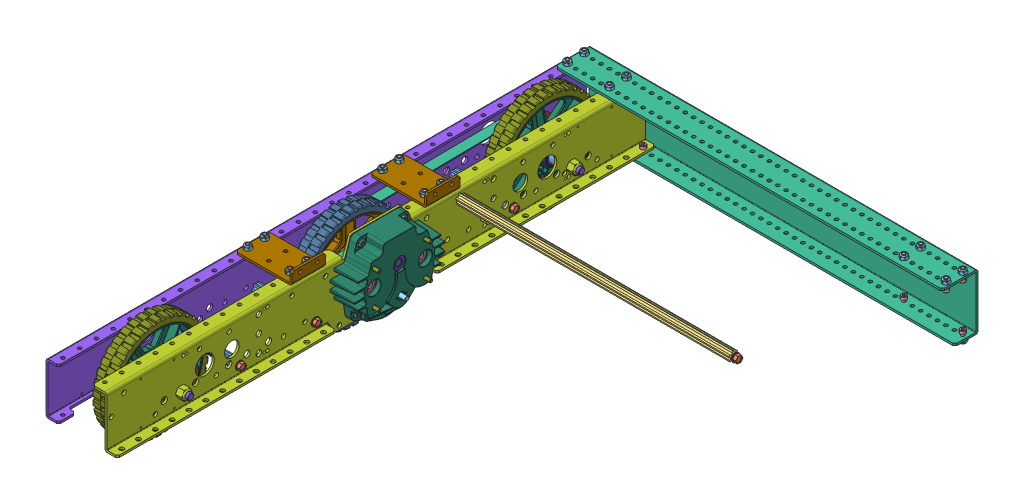
SolidWorks assembly AM14U3Long_Half, configuration Default. Lengths in mm.
Overall size (596.72 219.18 816.74).
154 component instances, 37 part files, 6 mates.
Components (placement in the parent):
- AM14U3Long_Frame_Half-1: AM14U3Long_Frame_Half [Default] at (0 136.144 -762.762) size (596.14 116.33 816.74)
  - 500Churro_3.375-1: 500Churro_3.375 [Default] at (-501.65 -66.929 448.437) x (0 0 1) z (-1 0 0) size (14.66 12.7 85.72)
  - 500Churro_3.375-2: 500Churro_3.375 [Default] at (-501.65 -66.929 562.737) x (0 0 1) z (-1 0 0) size (14.66 12.7 85.72)
  - 500Churro_3.375-3: 500Churro_3.375 [Default] at (-501.65 -66.929 264.287) x (0 0 1) z (-1 0 0) size (14.66 12.7 85.72)
  - 500Churro_3.375-4: 500Churro_3.375 [Default] at (-501.65 -66.929 149.987) x (0 0 1) z (-1 0 0) size (14.66 12.7 85.72)
  - ThreadRollingScrew_0.25-20x0.75_FHTS 0.25-20-G-0.75-C-1: ThreadRollingScrew_0.25-20x0.75_FHTS 0.25-20-G-0.75-C [Default] at (-498.475 -66.929 562.737) x (-1 0 0) z (0 0.924225 0.381849) size (24.64 12.19 12.19)
  - ThreadRollingScrew_0.25-20x0.75_FHTS 0.25-20-G-0.75-C-2: ThreadRollingScrew_0.25-20x0.75_FHTS 0.25-20-G-0.75-C [Default] at (-498.475 -66.929 448.437) x (-1 0 0) z (0 0.924225 0.381849) size (24.64 12.19 12.19)
  - ThreadRollingScrew_0.25-20x0.75_FHTS 0.25-20-G-0.75-C-3: ThreadRollingScrew_0.25-20x0.75_FHTS 0.25-20-G-0.75-C [Default] at (-498.475 -66.929 264.287) x (-1 0 0) z (0 0.924225 0.381849) size (24.64 12.19 12.19)
  - ThreadRollingScrew_0.25-20x0.75_FHTS 0.25-20-G-0.75-C-4: ThreadRollingScrew_0.25-20x0.75_FHTS 0.25-20-G-0.75-C [Default] at (-498.475 -66.929 149.987) x (-1 0 0) z (0 0.924225 0.381849) size (24.64 12.19 12.19)
  - ThreadRollingScrew_0.25-20x0.75_FHTS 0.25-20-G-0.75-C-5: ThreadRollingScrew_0.25-20x0.75_FHTS 0.25-20-G-0.75-C [Default] at (-590.55 -66.929 562.737) size (24.64 12.19 12.19)
  - ThreadRollingScrew_0.25-20x0.75_FHTS 0.25-20-G-0.75-C-6: ThreadRollingScrew_0.25-20x0.75_FHTS 0.25-20-G-0.75-C [Default] at (-590.55 -66.929 448.437) size (24.64 12.19 12.19)
  - ThreadRollingScrew_0.25-20x0.75_FHTS 0.25-20-G-0.75-C-7: ThreadRollingScrew_0.25-20x0.75_FHTS 0.25-20-G-0.75-C [Default] at (-590.55 -66.929 149.987) size (24.64 12.19 12.19)
  - ThreadRollingScrew_0.25-20x0.75_FHTS 0.25-20-G-0.75-C-8: ThreadRollingScrew_0.25-20x0.75_FHTS 0.25-20-G-0.75-C [Default] at (-590.55 -66.929 264.287) size (24.64 12.19 12.19)
  - ThreadRollingScrew_0.25-20x0.75_FHTS 0.25-20-G-0.75-C-9: ThreadRollingScrew_0.25-20x0.75_FHTS 0.25-20-G-0.75-C [Default] at (-501.65 -15.494 229.362) size (24.64 12.19 12.19)
  - ThreadRollingScrew_0.25-20x0.75_FHTS 0.25-20-G-0.75-C-10: ThreadRollingScrew_0.25-20x0.75_FHTS 0.25-20-G-0.75-C [Default] at (-82.55 -15.494 229.362) x (-1 0 0) z (0 -0.924225 -0.381849) size (24.64 12.19 12.19)
  - 500Churro_cut_16.25-1: 500Churro_cut_16.25 [Default] at (-85.725 -15.494 229.362) x (0 0.99241 0.122972) z (-1 0 0) size (14.66 12.7 412.75)
  - Screw_SHCS_10-32x0.5_HX-SHCS 0.19-32x1.375x1-C-1: Screw_SHCS_10-32x0.5_HX-SHCS 0.19-32x1.375x1-C [Default] at (-577.85 -11.43 -11.938) x (0 1 0) z (0 0 1) size (17.53 7.94 7.94)
  - Screw_SHCS_10-32x0.5_HX-SHCS 0.19-32x1.375x1-C-2: Screw_SHCS_10-32x0.5_HX-SHCS 0.19-32x1.375x1-C [Default] at (-577.85 -11.43 -37.338) x (0 1 0) z (0 0 1) size (17.53 7.94 7.94)
  - Screw_SHCS_10-32x0.5_HX-SHCS 0.19-32x1.375x1-C-3: Screw_SHCS_10-32x0.5_HX-SHCS 0.19-32x1.375x1-C [Default] at (-514.35 -11.43 -37.338) x (0 1 0) z (0 0 1) size (17.53 7.94 7.94)
  - Screw_SHCS_10-32x0.5_HX-SHCS 0.19-32x1.375x1-C-4: Screw_SHCS_10-32x0.5_HX-SHCS 0.19-32x1.375x1-C [Default] at (-514.35 -11.43 -11.938) x (0 1 0) z (0 0 1) size (17.53 7.94 7.94)
  - Screw_SHCS_10-32x0.5_HX-SHCS 0.19-32x1.375x1-C-5: Screw_SHCS_10-32x0.5_HX-SHCS 0.19-32x1.375x1-C [Default] at (-488.95 -73.152 -37.338) x (0 -1 0) z (0 0 1) size (17.53 7.94 7.94)
  - Screw_SHCS_10-32x0.5_HX-SHCS 0.19-32x1.375x1-C-6: Screw_SHCS_10-32x0.5_HX-SHCS 0.19-32x1.375x1-C [Default] at (-577.85 -73.152 -37.338) x (0 -1 0) z (0 0 1) size (17.53 7.94 7.94)
  - Screw_SHCS_10-32x0.5_HX-SHCS 0.19-32x1.375x1-C-7: Screw_SHCS_10-32x0.5_HX-SHCS 0.19-32x1.375x1-C [Default] at (-6.35 -11.176 -11.938) x (0 1 0) z (-0.991845 0 0.127447) size (17.53 7.94 7.94)
  - Screw_SHCS_10-32x0.5_HX-SHCS 0.19-32x1.375x1-C-8: Screw_SHCS_10-32x0.5_HX-SHCS 0.19-32x1.375x1-C [Default] at (-6.35 -11.176 -37.338) x (0 1 0) z (0.595464 0 0.803382) size (17.53 7.94 7.94)
  - Screw_SHCS_10-32x0.5_HX-SHCS 0.19-32x1.375x1-C-9: Screw_SHCS_10-32x0.5_HX-SHCS 0.19-32x1.375x1-C [Default] at (-69.85 -11.176 -11.938) x (0 1 0) z (0.578861 0 0.815426) size (17.53 7.94 7.94)
  - Screw_SHCS_10-32x0.5_HX-SHCS 0.19-32x1.375x1-C-10: Screw_SHCS_10-32x0.5_HX-SHCS 0.19-32x1.375x1-C [Default] at (-69.85 -11.176 -37.338) x (0 1 0) z (0.958905 0 0.283727) size (17.53 7.94 7.94)
  - Screw_SHCS_10-32x0.5_HX-SHCS 0.19-32x1.375x1-C-11: Screw_SHCS_10-32x0.5_HX-SHCS 0.19-32x1.375x1-C [Default] at (-6.35 -73.406 -37.338) x (0 -1 0) z (-0.989362 0 -0.145473) size (17.53 7.94 7.94)
  - Screw_SHCS_10-32x0.5_HX-SHCS 0.19-32x1.375x1-C-12: Screw_SHCS_10-32x0.5_HX-SHCS 0.19-32x1.375x1-C [Default] at (-95.25 -73.406 -37.338) x (0 -1 0) z (-0.875347 0 0.483496) size (17.53 7.94 7.94)
  - NylockNut_10-32-1: NylockNut_10-32 [Default] at (-69.85 0 -11.938) x (1 0 0) z (0 1 0) size (9.53 11 5.96)
  - NylockNut_10-32-2: NylockNut_10-32 [Default] at (-69.85 0 -37.338) x (1 0 0) z (0 1 0) size (9.53 11 5.96)
  - NylockNut_10-32-3: NylockNut_10-32 [Default] at (-6.35 0 -37.338) x (1 0 0) z (0 1 0) size (9.53 11 5.96)
  - NylockNut_10-32-4: NylockNut_10-32 [Default] at (-6.35 0 -11.938) x (1 0 0) z (0 1 0) size (9.53 11 5.96)
  - NylockNut_10-32-5: NylockNut_10-32 [Default] at (-6.35 -84.582 -37.338) x (1 0 0) z (0 -1 0) size (9.53 11 5.96)
  - NylockNut_10-32-6: NylockNut_10-32 [Default] at (-95.25 -84.582 -37.338) x (1 0 0) z (0 -1 0) size (9.53 11 5.96)
  - NylockNut_10-32-7: NylockNut_10-32 [Default] at (-514.35 0 -11.938) x (1 0 0) z (0 1 0) size (9.53 11 5.96)
  - NylockNut_10-32-8: NylockNut_10-32 [Default] at (-514.35 0 -37.338) x (1 0 0) z (0 1 0) size (9.53 11 5.96)
  - NylockNut_10-32-9: NylockNut_10-32 [Default] at (-577.85 0 -37.338) x (1 0 0) z (0 1 0) size (9.53 11 5.96)
  - NylockNut_10-32-10: NylockNut_10-32 [Default] at (-577.85 0 -11.938) x (1 0 0) z (0 1 0) size (9.53 11 5.96)
  - NylockNut_10-32-11: NylockNut_10-32 [Default] at (-488.95 -84.582 -37.338) x (1 0 0) z (0 -1 0) size (9.53 11 5.96)
  - NylockNut_10-32-12: NylockNut_10-32 [Default] at (-577.85 -84.582 -37.338) x (1 0 0) z (0 -1 0) size (9.53 11 5.96)
  - Screw_SHCS_10-32x0.5_HX-SHCS 0.19-32x1.375x1-C-13: Screw_SHCS_10-32x0.5_HX-SHCS 0.19-32x1.375x1-C [Default] at (-577.85 -11.43 445.262) x (0 1 0) z (0 0 1) size (17.53 7.94 7.94)
  - Screw_SHCS_10-32x0.5_HX-SHCS 0.19-32x1.375x1-C-14: Screw_SHCS_10-32x0.5_HX-SHCS 0.19-32x1.375x1-C [Default] at (-577.85 -11.43 470.662) x (0 1 0) z (0 0 1) size (17.53 7.94 7.94)
  - Screw_SHCS_10-32x0.5_HX-SHCS 0.19-32x1.375x1-C-15: Screw_SHCS_10-32x0.5_HX-SHCS 0.19-32x1.375x1-C [Default] at (-514.35 -11.43 445.262) x (0 1 0) z (0 0 1) size (17.53 7.94 7.94)
  - Screw_SHCS_10-32x0.5_HX-SHCS 0.19-32x1.375x1-C-16: Screw_SHCS_10-32x0.5_HX-SHCS 0.19-32x1.375x1-C [Default] at (-514.35 -11.43 470.662) x (0 1 0) z (0 0 1) size (17.53 7.94 7.94)
  - Screw_SHCS_10-32x0.5_HX-SHCS 0.19-32x1.375x1-C-17: Screw_SHCS_10-32x0.5_HX-SHCS 0.19-32x1.375x1-C [Default] at (-577.85 -11.43 267.462) x (0 1 0) z (0 0 1) size (17.53 7.94 7.94)
  - Screw_SHCS_10-32x0.5_HX-SHCS 0.19-32x1.375x1-C-18: Screw_SHCS_10-32x0.5_HX-SHCS 0.19-32x1.375x1-C [Default] at (-577.85 -11.43 242.062) x (0 1 0) z (0 0 1) size (17.53 7.94 7.94)
  - Screw_SHCS_10-32x0.5_HX-SHCS 0.19-32x1.375x1-C-19: Screw_SHCS_10-32x0.5_HX-SHCS 0.19-32x1.375x1-C [Default] at (-514.35 -11.43 242.062) x (0 1 0) z (0 0 1) size (17.53 7.94 7.94)
  - Screw_SHCS_10-32x0.5_HX-SHCS 0.19-32x1.375x1-C-20: Screw_SHCS_10-32x0.5_HX-SHCS 0.19-32x1.375x1-C [Default] at (-514.35 -11.43 267.462) x (0 1 0) z (0 0 1) size (17.53 7.94 7.94)
  - NylockNut_10-32-13: NylockNut_10-32 [Default] at (-514.35 -0.254 267.462) x (1 0 0) z (0 1 0) size (9.53 11 5.96)
  - NylockNut_10-32-14: NylockNut_10-32 [Default] at (-514.35 -0.254 242.062) x (1 0 0) z (0 1 0) size (9.53 11 5.96)
  - NylockNut_10-32-15: NylockNut_10-32 [Default] at (-577.85 -0.254 267.462) x (1 0 0) z (0 1 0) size (9.53 11 5.96)
  - NylockNut_10-32-16: NylockNut_10-32 [Default] at (-577.85 -0.254 242.062) x (1 0 0) z (0 1 0) size (9.53 11 5.96)
  - NylockNut_10-32-17: NylockNut_10-32 [Default] at (-514.35 -0.254 470.662) x (1 0 0) z (0 1 0) size (9.53 11 5.96)
  - NylockNut_10-32-18: NylockNut_10-32 [Default] at (-577.85 -0.254 470.662) x (1 0 0) z (0 1 0) size (9.53 11 5.96)
  - NylockNut_10-32-19: NylockNut_10-32 [Default] at (-577.85 -0.254 445.262) x (1 0 0) z (0 1 0) size (9.53 11 5.96)
  - NylockNut_10-32-20: NylockNut_10-32 [Default] at (-514.35 -0.254 445.262) x (1 0 0) z (0 1 0) size (9.53 11 5.96)
  - AM14U3EndPlate_Long-1: AM14U3EndPlate_Long [Default] at (-488.098 60.9785 -76.8664) x (1 0 0) z (0 -1 0) size (584.2 53.97 84.58)
  - AM14U3InnerPlate_Long-1: AM14U3InnerPlate_Long [Default] at (-501.65 -77.216 762.762) x (0 0 -1) z (0 -1 0) size (812.8 38.1 116.33)
  - AM14U3OuterPlate_Long_DefaultSM-FLAT-PATTERN-1: AM14U3OuterPlate_Long_DefaultSM-FLAT-PATTERN [Default] at (-587.375 -77.216 -50.038) x (0 0 1) z (0 -1 0) size (812.8 19.05 77.72)
  - Bracket_2x3-1: Bracket_2x3 [Default] at (-584.2 -3.429 496.062) size (85.72 19.05 50.8)
  - Bracket_2x3-2: Bracket_2x3 [Default] at (-584.2 -3.429 292.862) size (85.72 19.05 50.8)
- ToughboxMini-1: ToughboxMini [Default] at (-549.0167 66.1299 -315.2992) x (0 0.001296 0.999999) z (-1 0 0) size (140.05 131.62 142.29)
  - TBMiniSmallHexShaft-1: TBMiniSmallHexShaft [Default] at (-127.8104 29.3671 -52.3959) x (-0.59657 -0.802561 0) z (-0.802561 0.59657 0) size (11 38.23 9.52)
  - ToughboxLargeClusterGear_Hex_50t0.375-1: ToughboxLargeClusterGear_Hex_50t0.375 [Default] at (-91.0349 50.9043 -67.5597) x (-0.59657 -0.802561 0) z (0 0 -1) size (65.97 66.04 10.34)
  - Bearing_FR6ZZ-1: Bearing_FR6ZZ [Default] at (-96.247 60.278 -52.5991) x (-0.893862 0.448342 0) z (0 0 1) size (24.69 24.69 7.16)
  - NylockNut_10-32-1: NylockNut_10-32 [Default] at (-129.8464 -8.0737 -56.3837) x (0.501678 0.865055 0) z (0 0 -1) size (9.53 11 5.96)
  - NylockNut_10-32-2: NylockNut_10-32 [Default] at (-59.2462 80.7349 -56.3837) x (0.999999 -0.001296 0) z (0 0 -1) size (9.53 11 5.96)
  - NylockNut_10-32-3: NylockNut_10-32 [Default] at (-122.7461 80.8172 -56.3837) x (0.500567 0.865698 0) z (0 0 -1) size (9.53 11 5.96)
  - NylockNut_10-32-4: NylockNut_10-32 [Default] at (-52.3764 -8.1741 -56.3837) x (-0.501678 -0.865055 0) z (0 0 -1) size (9.53 11 5.96)
  - Washer_5-16-1: Washer_5-16 [Default] at (-52.3162 38.3079 -77.7705) x (0.171117 0.985251 0) z (0 0 -1) size (17.53 17.53 1.47)
  - Washer_5-16-2: Washer_5-16 [Default] at (-52.3162 38.3079 -76.2973) x (0.897267 -0.441488 0) z (0 0 -1) size (17.53 17.53 1.47)
  - Washer_5-16-3: Washer_5-16 [Default] at (-129.7861 38.4083 -77.7705) x (-0.990116 0.140253 0) z (0 0 1) size (17.53 17.53 1.47)
  - Washer_5-16-4: Washer_5-16 [Default] at (-129.7861 38.4083 -79.2437) x (-0.681761 0.731575 0) z (0 0 1) size (17.53 17.53 1.47)
  - CIMGear_14t8mm-1: CIMGear_14t8mm [Default] at (-52.3162 38.3079 -63.5973) x (-0.998626 0.052407 0) z (0 0 -1) size (20.03 20.32 12.7)
  - CIMGear_14t8mm-2: CIMGear_14t8mm [Default] at (-129.7861 38.4083 -63.5973) x (-0.70887 0.705339 0) z (0 0 -1) size (20.03 20.32 12.7)
  - TBMiniHousing-1: TBMiniHousing [Default] at (-91.0876 10.1882 -86.3557) x (0.999999 -0.001296 0) z (0 0 1) size (139.9 118.55 41.62)
  - Screw_SHCS_10-32x0.625-1: Screw_SHCS_10-32x0.625 [Default] at (-52.2832 63.7078 -74.4685) x (-0.564778 -0.825243 0) z (-0.825243 0.564778 0) size (7.82 20.65 7.82)
  - Screw_SHCS_10-32x0.625-2: Screw_SHCS_10-32x0.625 [Default] at (-122.7461 80.8172 -42.5915) x (0.507484 -0.861661 0) z (-0.861661 -0.507484 0) size (7.82 20.65 7.82)
  - Screw_SHCS_10-32x0.625-3: Screw_SHCS_10-32x0.625 [Default] at (-52.3764 -8.1741 -42.5915) x (0.507484 -0.861661 0) z (-0.861661 -0.507484 0) size (7.82 20.65 7.82)
  - Screw_SHCS_10-32x0.625-4: Screw_SHCS_10-32x0.625 [Default] at (-129.8464 -8.0737 -42.5915) x (0.507484 -0.861661 0) z (-0.861661 -0.507484 0) size (7.82 20.65 7.82)
  - Screw_SHCS_10-32x0.625-5: Screw_SHCS_10-32x0.625 [Default] at (-59.2462 80.7349 -42.5915) x (0.740711 -0.671824 0) z (-0.671824 -0.740711 0) size (7.82 20.65 7.82)
  - Screw_SHCS_10-32x0.625-6: Screw_SHCS_10-32x0.625 [Default] at (-52.3491 12.9079 -74.4685) x (-0.564778 -0.825243 0) z (-0.825243 0.564778 0) size (7.82 20.65 7.82)
  - Screw_SHCS_10-32x0.625-7: Screw_SHCS_10-32x0.625 [Default] at (-129.7532 63.8083 -74.4685) x (-0.966277 -0.257503 0) z (-0.257503 0.966277 0) size (7.82 20.65 7.82)
  - Screw_SHCS_10-32x0.625-8: Screw_SHCS_10-32x0.625 [Default] at (-129.819 13.0083 -74.4685) x (-0.99652 0.083357 0) z (0.083357 0.99652 0) size (7.82 20.65 7.82)
  - Bearing_R6ZZ-1: Bearing_R6ZZ [Default] at (-91.0349 50.9043 -84.8317) x (0.958138 -0.286306 0) z (0 0 1) size (22.23 22.23 7.11)
  - Bearing_R6ZZ-2: Bearing_R6ZZ [Default] at (-91.0876 10.1882 -84.8317) x (-0.661529 0.74992 0) z (0 0 1) size (22.23 22.23 7.11)
  - RetainingClip-1: RetainingClip [Default] at (-129.7861 38.4083 -63.5973) x (0 0 1) z (-1 0 0) size (1.12 14.83 14.83)
  - RetainingClip-2: RetainingClip [Default] at (-52.3162 38.3079 -63.5973) x (0 0 1) z (-1 0 0) size (1.12 14.83 14.83)
  - ExternalKlipring-1: ExternalKlipring [Default] at (-91.0876 10.1882 -64.4355) x (0.996411 -0.084651 0) z (0 0 1) size (19.07 20.96 1.27)
  - Bearing_Hex_FR8ZZ-1: Bearing_Hex_FR8ZZ [Default] at (-91.0876 10.1882 -44.6717) x (0.188693 -0.982036 0) z (0 0 -1) size (31.12 31.12 7.93)
  - SmallClusterGear_Hex_16t0.375-1: SmallClusterGear_Hex_16t0.375 [Default] at (-91.0349 50.9043 -67.5597) x (0 0 1) z (0.396753 -0.917925 0) size (15.19 22.57 22.57)
  - LargeOutputGear_Hex_48t0.5-1: LargeOutputGear_Hex_48t0.5 [Default] at (-91.0876 10.1882 -63.1655) x (0 0 1) z (0.756122 0.654431 0) size (10.21 63.42 63.42)
  - TBMiniHexOutputShaft-1: TBMiniHexOutputShaft [Default] at (-100.2289 -30.5762 -52.3197) x (0.188693 -0.982036 0) z (-0.982036 -0.188693 0) size (14.66 142.29 12.7)
- Bearing_Hex_FR8ZZ-1: Bearing_Hex_FR8ZZ [Default] at (-593.7783 76.2 -406.4) x (0 0.32638 -0.945239) z (1 0 0) size (31.12 31.12 7.93)
- Belt_15mm_Long-1: Belt_15mm_Long [Default] at (-511.5261 79.756 -111.3496) x (0 -0.012051 -0.999927) z (0 0.999927 -0.012051) size (368.15 15 73.08)
- Belt_15mm_Long-2: Belt_15mm_Long [Default] at (-576.9127 76.2 -406.4) x (0 0.012051 -0.999927) z (0 -0.999927 -0.012051) size (368.15 15 73.08)
- NylockNut_0.375-16_91831A127-1: NylockNut_0.375-16_91831A127 [Default] at (-498.475 79.756 -701.4504) x (0 -1 0) z (0 0 1) size (14.29 12 16.5)
- NylockNut_0.375-16_91831A127-2: NylockNut_0.375-16_91831A127 [Default] at (-498.475 79.7563 -111.3496) x (0 -1 0) z (0 0 1) size (14.29 12 16.5)
- HHSBolt_0.375-16x4.25_HFBOLT 0.375-16x2.5x1-C-1: HHSBolt_0.375-16x4.25_HFBOLT 0.375-16x2.5x1-C [Default] at (-596.7222 79.756 -111.3496) size (114.12 16.48 14.27)
- HHSBolt_0.375-16x4.25_HFBOLT 0.375-16x2.5x1-C-2: HHSBolt_0.375-16x4.25_HFBOLT 0.375-16x2.5x1-C [Default] at (-596.7222 79.756 -701.4504) x (1 0 0) z (0 -0.203423 -0.979091) size (114.12 16.48 14.27)
- Wheel_6inHiGrip_Center-1: Wheel_6inHiGrip_Center [Default] at (-513.0653 208.3565 -483.6317) x (-1 0 0) z (0 -0.493281 0.86987) size (81.42 191.55 191.55)
  - Wheel_6inHiGrip-1: Wheel_6inHiGrip [Default] at (83.7987 67.439 110.9939) size (34.93 191.55 191.55)
    - Wheel_6inHiGrip_Wheel-1: Wheel_6inHiGrip_Wheel [Default] at (-52.6446 9.4231 21.378) size (34.93 132.08 132.08)
    - Wheel_6inHiGrip_Tread-1: Wheel_6inHiGrip_Tread [Default] at (-65.3446 9.4231 21.378) x (0 -0.304368 -0.952555) z (1 0 0) size (152.4 152.4 25.58)
  - HalfPulley_42t5mm-1: HalfPulley_42t5mm [Default] at (47.6006 76.862 132.3719) x (1 0 0) z (0 -0.5 0.866025) size (13 74.23 74.23)
  - HalfPulley_42t5mm-2: HalfPulley_42t5mm [Default] at (64.263 76.862 132.3719) x (-1 0 0) z (0 -0.499927 0.866067) size (13 74.23 74.23)
  - ThreadFormingScrew_10-24x1.25_93882A213-1: ThreadFormingScrew_10-24x1.25_93882A213 [Default] at (63.247 76.8605 108.5602) x (0 0.953802 -0.300437) z (1 0 0) size (10.52 10.52 35.59)
  - ThreadFormingScrew_10-24x1.25_93882A213-2: ThreadFormingScrew_10-24x1.25_93882A213 [Default] at (63.247 97.4833 120.4656) x (0 0.953802 -0.300437) z (1 0 0) size (10.52 10.52 35.59)
  - ThreadFormingScrew_10-24x1.25_93882A213-3: ThreadFormingScrew_10-24x1.25_93882A213 [Default] at (63.247 56.2398 144.2799) x (0 0.953802 -0.300437) z (1 0 0) size (10.52 10.52 35.59)
  - ThreadFormingScrew_10-24x1.25_93882A213-4: ThreadFormingScrew_10-24x1.25_93882A213 [Default] at (63.247 76.8625 156.1852) x (0 -0.013882 -0.999904) z (1 0 0) size (10.52 10.52 35.59)
  - ThreadFormingScrew_10-24x1.25_93882A213-5: ThreadFormingScrew_10-24x1.25_93882A213 [Default] at (63.247 97.4843 144.2781) x (0 -0.733065 -0.680158) z (1 0 0) size (10.52 10.52 35.59)
  - ThreadFormingScrew_10-24x1.25_93882A213-6: ThreadFormingScrew_10-24x1.25_93882A213 [Default] at (63.247 56.2388 120.4674) x (0 0.407306 -0.913292) z (1 0 0) size (10.52 10.52 35.59)
  - HalfPulley_42t5mm-3: HalfPulley_42t5mm [Default] at (-1.9548 76.862 132.3719) x (1 0 0) z (0 -1 -0.000063) size (13 74.23 74.23)
  - HalfPulley_42t5mm-4: HalfPulley_42t5mm [Default] at (14.7076 76.862 132.3719) x (-1 0 0) z (0 -1 0.000021) size (13 74.23 74.23)
  - HexHub_500EX-1: HexHub_500EX [Default] at (-8.3048 76.862 132.3719) x (0 -0.866025 -0.5) z (0 -0.5 0.866025) size (55.37 25.4 51.33)
  - ThreadFormingScrew_10-24x1.25_93882A213-7: ThreadFormingScrew_10-24x1.25_93882A213 [Default] at (-5.2568 97.4843 120.4656) x (0 -0.953802 0.300437) z (-1 0 0) size (10.52 10.52 35.59)
  - ThreadFormingScrew_10-24x1.25_93882A213-8: ThreadFormingScrew_10-24x1.25_93882A213 [Default] at (-5.2568 76.862 108.5594) x (0 -0.953802 0.300437) z (-1 0 0) size (10.52 10.52 35.59)
  - ThreadFormingScrew_10-24x1.25_93882A213-9: ThreadFormingScrew_10-24x1.25_93882A213 [Default] at (-5.2568 56.2398 120.4656) x (0 -0.953802 0.300437) z (-1 0 0) size (10.52 10.52 35.59)
  - ThreadFormingScrew_10-24x1.25_93882A213-10: ThreadFormingScrew_10-24x1.25_93882A213 [Default] at (-5.2568 97.4843 144.2781) x (0 -0.192002 -0.981394) z (-1 0 0) size (10.52 10.52 35.59)
  - ThreadFormingScrew_10-24x1.25_93882A213-11: ThreadFormingScrew_10-24x1.25_93882A213 [Default] at (-5.2568 56.2398 144.2781) x (0 -0.986288 0.16503) z (-1 0 0) size (10.52 10.52 35.59)
  - ThreadFormingScrew_10-24x1.25_93882A213-12: ThreadFormingScrew_10-24x1.25_93882A213 [Default] at (-5.2568 76.862 156.1844) x (0 -0.150217 -0.988653) z (-1 0 0) size (10.52 10.52 35.59)
  - Spacer_Hex_0.57x0.5-1: Spacer_Hex_0.57x0.5 [Default] at (57.8495 76.862 132.3719) x (0 -0.866025 -0.5) z (0 -0.5 0.866025) size (28.55 14.48 28.55)
- 6 HiGrip with bearings, pulleys and spacers-1: 6 HiGrip with bearings, pulleys and spacers [Default] at (-574.9579 3.6159 21.4388) x (1 0 0) z (0 0.865776 -0.500432) size (85.56 152.4 152.4)
  - 6 HiGrip Wheel Assembly Rev II-1: 6 HiGrip Wheel Assembly Rev II [Default] at (83.7987 67.439 110.9939) size (34.93 152.4 152.4)
    - 6 wheel Rev 4-1: 6 wheel Rev 4 [Default] at (-52.6446 9.4231 21.378) size (34.93 132.08 132.08)
    - 6 wheel tread II-1: 6 wheel tread II [Default] at (-65.3446 9.4231 21.378) x (0 0 -1) z (1 0 0) size (152.4 152.4 25.58)
  - HalfPulley_42t5mm-1: HalfPulley_42t5mm [Default] at (47.6006 76.862 132.3719) x (1 0 0) z (0 -0.5 0.866025) size (13 74.23 74.23)
  - HalfPulley_42t5mm-2: HalfPulley_42t5mm [Default] at (64.263 76.862 132.3719) x (-1 0 0) z (0 -0.499927 0.866067) size (13 74.23 74.23)
  - Bearing_1614ZZ-1: Bearing_1614ZZ [Default] at (62.612 76.862 132.3719) x (0 0.904908 -0.425608) z (-1 0 0) size (28.58 28.58 9.53)
  - Bearing_1614ZZ-2: Bearing_1614ZZ [Default] at (15.2791 76.862 132.3719) x (0 0.960548 -0.278115) z (1 0 0) size (28.58 28.58 9.53)
  - Washer_5-16-1: Washer_5-16 [Default] at (63.247 76.8605 108.5602) x (0 -0.624545 -0.780988) z (1 0 0) size (17.53 17.53 1.47)
  - Washer_5-16-2: Washer_5-16 [Default] at (63.247 97.4833 120.4656) x (0 -0.995817 0.091369) z (1 0 0) size (17.53 17.53 1.47)
  - Washer_5-16-3: Washer_5-16 [Default] at (63.247 56.2398 144.2799) x (0 0.546149 0.837688) z (1 0 0) size (17.53 17.53 1.47)
  - Washer_5-16-4: Washer_5-16 [Default] at (63.247 76.8625 156.1852) x (0 0.642695 -0.766122) z (1 0 0) size (17.53 17.53 1.47)
  - Washer_5-16-5: Washer_5-16 [Default] at (63.247 97.4843 144.2781) x (0 0.936259 -0.351311) z (1 0 0) size (17.53 17.53 1.47)
  - Washer_5-16-6: Washer_5-16 [Default] at (63.247 56.2388 120.4674) x (0 -0.160557 -0.987027) z (1 0 0) size (17.53 17.53 1.47)
  - Spacer_0.28x0.382-1: Spacer_0.28x0.382 [Default] at (74.4865 76.862 132.3719) x (0 -0.996837 -0.07947) z (-1 0 0) size (13.16 13.16 7.11)
  - Spacer_0.85x0.38-1: Spacer_0.85x0.38 [Default] at (-11.0734 76.862 132.3719) x (0 0.960548 -0.278115) z (1 0 0) size (19.05 19.05 21.59)
- 6 HiGrip with bearings, pulleys and spacers-2: 6 HiGrip with bearings, pulleys and spacers [Default] at (-513.4809 -62.9554 -646.1011) x (-1 0 0) z (0 0.624698 -0.780867) size (85.56 152.4 152.4)
  - 6 HiGrip Wheel Assembly Rev II-1: 6 HiGrip Wheel Assembly Rev II [Default] at (83.7987 67.439 110.9939) size (34.93 152.4 152.4)
    - 6 wheel Rev 4-1: 6 wheel Rev 4 [Default] at (-52.6446 9.4231 21.378) size (34.93 132.08 132.08)
    - 6 wheel tread II-1: 6 wheel tread II [Default] at (-65.3446 9.4231 21.378) x (0 0 -1) z (1 0 0) size (152.4 152.4 25.58)
  - HalfPulley_42t5mm-1: HalfPulley_42t5mm [Default] at (47.6006 76.862 132.3719) x (1 0 0) z (0 -0.5 0.866025) size (13 74.23 74.23)
  - HalfPulley_42t5mm-2: HalfPulley_42t5mm [Default] at (64.263 76.862 132.3719) x (-1 0 0) z (0 -0.499927 0.866067) size (13 74.23 74.23)
  - Bearing_1614ZZ-1: Bearing_1614ZZ [Default] at (62.612 76.862 132.3719) x (0 0.904908 -0.425608) z (-1 0 0) size (28.58 28.58 9.53)
  - Bearing_1614ZZ-2: Bearing_1614ZZ [Default] at (15.2791 76.862 132.3719) x (0 0.960548 -0.278115) z (1 0 0) size (28.58 28.58 9.53)
  - Washer_5-16-1: Washer_5-16 [Default] at (63.247 76.8605 108.5602) x (0 -0.624545 -0.780988) z (1 0 0) size (17.53 17.53 1.47)
  - Washer_5-16-2: Washer_5-16 [Default] at (63.247 97.4833 120.4656) x (0 -0.995817 0.091369) z (1 0 0) size (17.53 17.53 1.47)
  - Washer_5-16-3: Washer_5-16 [Default] at (63.247 56.2398 144.2799) x (0 0.546149 0.837688) z (1 0 0) size (17.53 17.53 1.47)
  - Washer_5-16-4: Washer_5-16 [Default] at (63.247 76.8625 156.1852) x (0 0.642695 -0.766122) z (1 0 0) size (17.53 17.53 1.47)
  - Washer_5-16-5: Washer_5-16 [Default] at (63.247 97.4843 144.2781) x (0 0.936259 -0.351311) z (1 0 0) size (17.53 17.53 1.47)
  - Washer_5-16-6: Washer_5-16 [Default] at (63.247 56.2388 120.4674) x (0 -0.160557 -0.987027) z (1 0 0) size (17.53 17.53 1.47)
  - Spacer_0.28x0.382-1: Spacer_0.28x0.382 [Default] at (74.4865 76.862 132.3719) x (0 -0.996837 -0.07947) z (-1 0 0) size (13.16 13.16 7.11)
  - Spacer_0.85x0.38-1: Spacer_0.85x0.38 [Default] at (-11.0734 76.862 132.3719) x (0 0.960548 -0.278115) z (1 0 0) size (19.05 19.05 21.59)
Mates (geometry in assembly coordinates):
- Concentric1: concentric anti-aligned: cylinder of HHSBolt_0.375-16x4.25_HFBOLT 0.375-16x2.5x1-C-1 through (-596.7222 79.756 -111.3496) axis (-1 0 0) radius 4.7625; cylinder of 6 HiGrip with bearings, pulleys and spacers-1/Spacer_0.28x0.382-1 through (-507.5834 79.756 -111.3496) axis (1 0 0) radius 4.8514
- Concentric2: concentric anti-aligned: cylinder of HHSBolt_0.375-16x4.25_HFBOLT 0.375-16x2.5x1-C-2 through (-596.7222 79.756 -701.4504) axis (-1 0 0) radius 4.7625; cylinder of 6 HiGrip with bearings, pulleys and spacers-2/Spacer_0.85x0.38-1 through (-523.9975 79.756 -701.4504) axis (1 0 0) radius 4.826
- Coincident1: coincident aligned: axis of Belt_15mm_Long-2 through (-561.9127 76.2 -406.4) axis (-1 0 0); axis of Wheel_6inHiGrip_Center-1/HalfPulley_42t5mm-2 through (-558.4587 76.2 -406.4) axis (-1 0 0)
- Width1: width anti-aligned: plane of Belt_15mm_Long-2 through (-561.9127 76.2 -406.4) normal (1 0 0); plane of Belt_15mm_Long-2 through (-576.9127 76.2 -406.4) normal (-1 0 0); plane of 6 HiGrip with bearings, pulleys and spacers-2/HalfPulley_42t5mm-2 through (-580.2839 47.6626 -706.3412) normal (-1 0 0); plane of 6 HiGrip with bearings, pulleys and spacers-2/HalfPulley_42t5mm-1 through (-558.5415 111.8498 -696.5623) normal (1 0 0)
- Width2: width anti-aligned: plane of Belt_15mm_Long-1 through (-511.5261 79.756 -111.3496) normal (1 0 0); plane of Belt_15mm_Long-2 through (-576.9127 76.2 -406.4) normal (-1 0 0); plane of Wheel_6inHiGrip_Center-1/HalfPulley_42t5mm-2 through (-579.8683 108.663 -406.6486) normal (-1 0 0); plane of Wheel_6inHiGrip_Center-1/HalfPulley_42t5mm-3 through (-508.5705 60.1879 -378.1596) normal (1 0 0)
- Width3: width anti-aligned: plane of Belt_15mm_Long-1 through (-526.5261 79.756 -111.3496) normal (-1 0 0); plane of Belt_15mm_Long-1 through (-511.5261 79.756 -111.3496) normal (1 0 0); plane of 6 HiGrip with bearings, pulleys and spacers-1/HalfPulley_42t5mm-2 through (-508.1549 79.7749 -78.8857) normal (1 0 0); plane of 6 HiGrip with bearings, pulleys and spacers-1/HalfPulley_42t5mm-1 through (-529.8973 79.7398 -143.8135) normal (-1 0 0)
